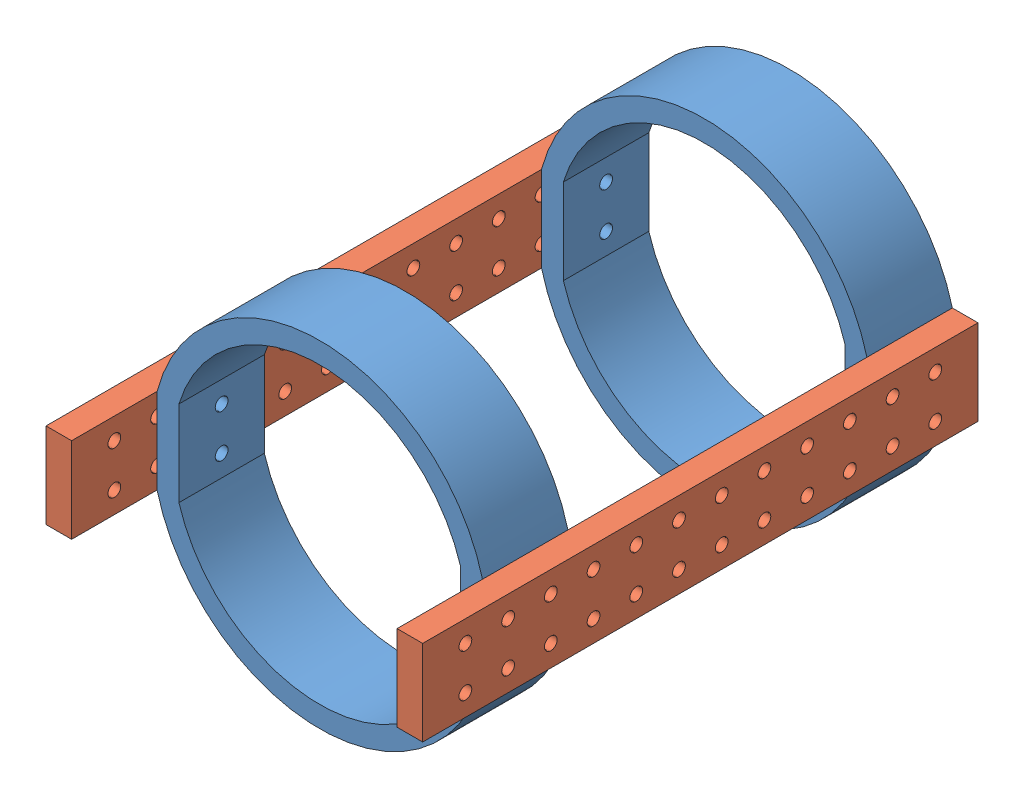
SolidWorks assembly Assem1, configuration Default. Lengths in mm.
Overall size (88.18 78.76 130).
4 component instances, 2 part files, 9 mates.
Components (placement in the parent):
- upper_arm_ring-1: upper_arm_ring [Default] at (38.6047 51.1661 38.7641) size (76.18 78.76 20)
- upper_arm_beam-1: upper_arm_beam [Default] at (76.6957 49.3312 108.0302) x (0 0 -1) z (1 0 0) size (130 20 6)
- upper_arm_beam-2: upper_arm_beam [Default] at (0.5137 49.3312 99.4981) x (0 0 1) z (-1 0 0) size (130 20 6)
- upper_arm_ring-2: upper_arm_ring [Default] at (38.6047 51.1661 128.7641) size (76.18 78.76 20)
Mates (geometry in assembly coordinates):
- Coincident1: coincident anti-aligned: plane of upper_arm_beam-1 through (76.6957 49.3312 108.0302) normal (-1 0 0); plane of upper_arm_ring-1 through (76.6957 61.1661 58.7641) normal (1 0 0)
- Concentric1: concentric aligned: circle of upper_arm_ring-1; circle of upper_arm_beam-1
- Concentric2: concentric anti-aligned: circle of upper_arm_ring-1; cylinder of upper_arm_beam-1 through (82.6957 46.1661 48.7641) axis (-1 0 0) radius 1.5
- Coincident8: coincident anti-aligned: plane of upper_arm_ring-1 through (0.5137 61.1661 58.7641) normal (-1 0 0); plane of upper_arm_beam-2 through (0.5137 49.3312 99.4981) normal (1 0 0)
- Concentric4: concentric aligned: cylinder of upper_arm_ring-1 through (0.5137 56.1661 48.7641) axis (1 0 0) radius 1.5; cylinder of upper_arm_beam-2 through (-5.4863 56.1661 48.7641) axis (1 0 0) radius 1.5
- Concentric5: concentric aligned: cylinder of upper_arm_ring-1 through (0.5137 46.1661 48.7641) axis (1 0 0) radius 1.5; cylinder of upper_arm_beam-2 through (-5.4863 46.1661 48.7641) axis (1 0 0) radius 1.5
- Coincident9: coincident: plane of upper_arm_beam-2 through (0.5137 49.3312 99.4981) normal (1 0 0); plane of upper_arm_ring-2 through (0.5137 61.1661 148.7641) normal (-1 0 0)
- Concentric6: concentric: circle of upper_arm_beam-2; circle of upper_arm_ring-2
- Concentric7: concentric anti-aligned: circle of upper_arm_beam-2; circle of upper_arm_ring-2
